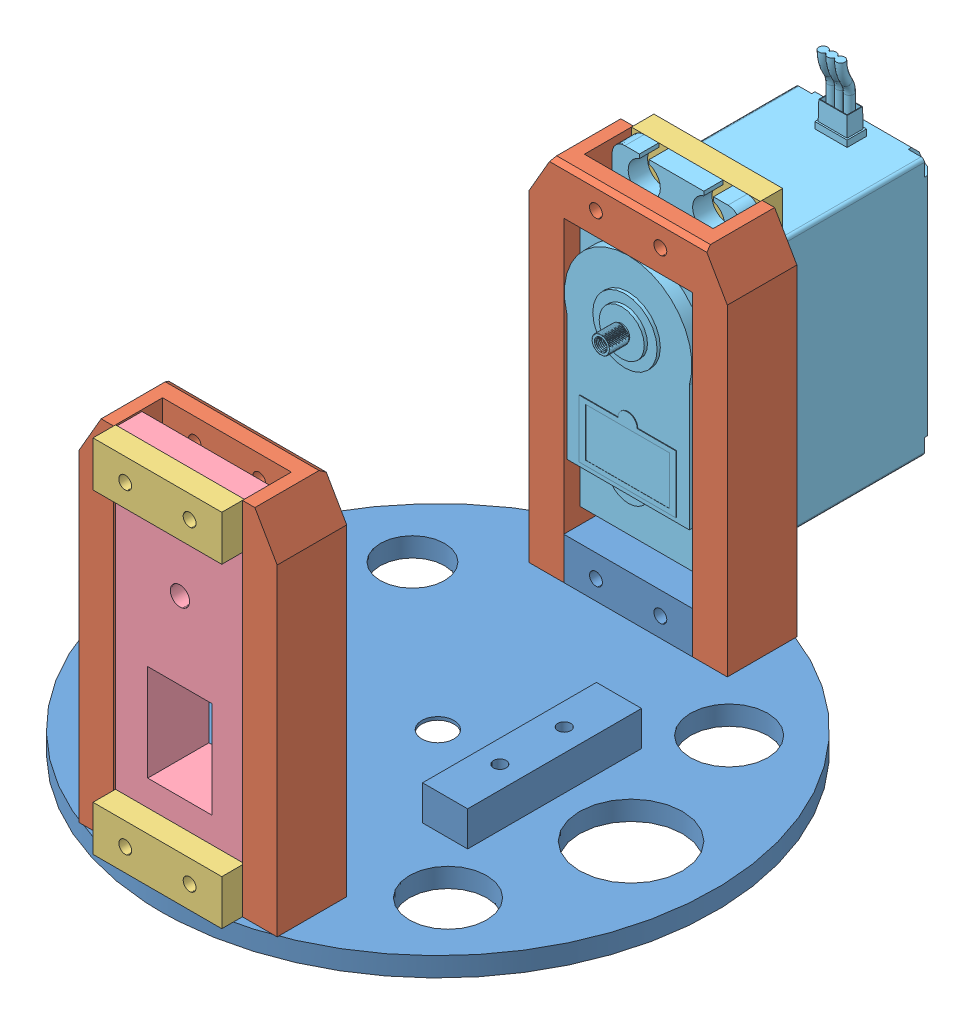
SolidWorks assembly Ensamblaje-Eslabon1, configuration Predeterminado. Lengths in mm.
Overall size (85.98 66.64 110.6).
9 component instances, 5 part files, 23 mates.
Components (placement in the parent):
- Tapa-Base-1: Tapa-Base [Predeterminado] at origin size (85.98 9.5 85.98)
- Agarre-Servo1-1: Agarre-Servo1 [Predeterminado] at (0.9903 29.0045 27.1089) x (0 1 0) z (1 0 0) size (66.64 13 30.8)
- Anclaje-Servo1-1: Anclaje-Servo1 [Predeterminado] at (-9.8767 2.5 -43.7911) x (1 0 0) z (0 -1 0) size (20 3.5 7)
- Soporte-Tama-Servo-1: Soporte-Tama-Servo [Predeterminado] at (0.2471 31.4955 39.8089) x (0 1 0) z (-1 0 0) size (55.5 16.4 20.07)
- Agarre-Servo1-2: Agarre-Servo1 [Predeterminado] at (-0.7438 29.0045 -27.5911) x (0 1 0) z (-1 0 0) size (66.64 13 30.8)
- Anclaje-Servo1-2: Anclaje-Servo1 [Predeterminado] at (-9.8767 52 -43.7911) x (1 0 0) z (0 -1 0) size (20 3.5 7)
- Anclaje-Servo1-3: Anclaje-Servo1 [Predeterminado] at (10.1233 10 39.8089) x (-1 0 0) z (0 1 0) size (20 3.5 7)
- Anclaje-Servo1-4: Anclaje-Servo1 [Predeterminado] at (-9.8767 52 39.8089) x (1 0 0) z (0 -1 0) size (20 3.5 7)
- MG996R-Servo-1: MG996R-Servo [Default] at (0.1233 32 -67.2911) x (0 1 0) z (1 0 0) size (58.18 41.75 20)
Mates (geometry in assembly coordinates):
- Coincidente2: coincident: plane of Tapa-Base-1 through (0.1337 3 -0.2313) normal (0 1 0); plane of Agarre-Servo1-2 through (15.5233 3 -35.1911) normal (0 -1 0)
- Coincidente3: coincident: plane of Tapa-Base-1 through (15.5233 2.5 0) normal (-1 0 0); plane of Agarre-Servo1-2 through (15.5233 0 -40.5911) normal (1 0 0)
- Coincidente4: coincident: plane of Tapa-Base-1 through (0 2.5 -35.1911) normal (0 0 1); plane of Agarre-Servo1-2 through (-0.7438 29.0045 -35.1911) normal (0 0 -1)
- Coincidente5: coincident: plane of Agarre-Servo1-2 through (12.0611 59 -40.5911) normal (0 1 0); plane of MG996R-Servo-1 through (0.1233 59 -67.2911) normal (0 1 0)
- Coincidente6: coincident: plane of Agarre-Servo1-2 through (10.1233 52 -40.5911) normal (-1 0 0); plane of MG996R-Servo-1 through (10.1233 12 -32.2911) normal (1 0 0)
- Coincidente7: coincident: plane of Anclaje-Servo1-2 through (-9.8767 52 -40.2911) normal (0 0 1); plane of MG996R-Servo-1 through (10.1233 59 -40.2911) normal (0 0 -1)
- Coincidente8: coincident: plane of Agarre-Servo1-2 through (12.0611 59 -40.5911) normal (0 1 0); plane of Anclaje-Servo1-2 through (-9.8767 59 -40.2911) normal (0 1 0)
- Coincidente9: coincident: plane of Agarre-Servo1-2 through (-9.8767 0 -40.5911) normal (1 0 0); plane of Anclaje-Servo1-2 through (-9.8767 52 -40.2911) normal (-1 0 0)
- Coincidente10: coincident: plane of Anclaje-Servo1-1 through (-9.8767 2.5 -40.2911) normal (0 0 1); plane of MG996R-Servo-1 through (-9.8767 5 -40.2911) normal (0 0 -1)
- Concéntrica1: concentric: cylinder of Tapa-Base-1 through (5.1233 6 -59.7911) axis (0 0 1) radius 1; cylinder of Anclaje-Servo1-1 through (5.1233 6 -40.2911) axis (0 0 -1) radius 1
- Coincidente12: coincident: plane of Agarre-Servo1-1 through (10.1233 0 40.1089) normal (-1 0 0); plane of Soporte-Tama-Servo-1 through (10.1233 3.25 34.7089) normal (1 0 0)
- Coincidente13: coincident: plane of Agarre-Servo1-1 through (10.1233 52 40.1089) normal (0 -1 0); plane of Soporte-Tama-Servo-1 through (10.1233 52 29.3089) normal (0 1 0)
- Concéntrica2: concentric: cylinder of Soporte-Tama-Servo-1 through (-4.8767 6.5 34.7089) axis (0 0 1) radius 1; cylinder of Anclaje-Servo1-3 through (-4.8767 6.5 42.3089) axis (0 0 -1) radius 1
- Coincidente14: coincident: plane of Soporte-Tama-Servo-1 through (0.2471 31.4955 38.8089) normal (0 0 1); plane of Anclaje-Servo1-3 through (10.1233 10 38.8089) normal (0 0 -1)
- Concéntrica3: concentric: cylinder of Soporte-Tama-Servo-1 through (5.1233 6.5 34.7089) axis (0 0 1) radius 1; cylinder of Anclaje-Servo1-3 through (5.1233 6.5 42.3089) axis (0 0 -1) radius 1
- Coincidente15: coincident: plane of Anclaje-Servo1-3 through (10.1233 10 42.3089) normal (0 0 1); plane of Anclaje-Servo1-4 through (-9.8767 52 42.3089) normal (0 0 1)
- Concéntrica4: concentric: cylinder of Soporte-Tama-Servo-1 through (5.1233 55.5 34.7089) axis (0 0 1) radius 1; cylinder of Anclaje-Servo1-4 through (5.1233 55.5 42.3089) axis (0 0 -1) radius 1
- Coincidente16: coincident: circle of Soporte-Tama-Servo-1; cylinder of Anclaje-Servo1-4 through (-4.8767 55.5 42.3089) axis (0 0 -1) radius 1
- Coincidente17: coincident: plane of Tapa-Base-1 through (0 2.5 34.7089) normal (0 0 -1); plane of Agarre-Servo1-1 through (0.9903 29.0045 34.7089) normal (0 0 1)
- Coincidente18: coincident: plane of Tapa-Base-1 through (0.1337 3 -0.2313) normal (0 1 0); plane of Agarre-Servo1-1 through (10.1233 3 34.7089) normal (0 -1 0)
- Coincidente19: coincident: plane of Tapa-Base-1 through (15.5233 2.5 0) normal (-1 0 0); plane of Agarre-Servo1-1 through (15.5233 53.0033 40.1089) normal (1 0 0)
- Distancia1: distance = 1 mm: plane of Agarre-Servo1-1 through (19.7233 0 29.3089) normal (0 0 -1); plane of Soporte-Tama-Servo-1 through (0.2471 31.4955 30.3089) normal (0 0 -1)
- Coincidente21: coincident: plane of Agarre-Servo1-2 through (-19.4767 0 -29.7911) normal (0 0 1); plane of MG996R-Servo-1 through (0.1233 32 -29.7911) normal (0 0 1)
